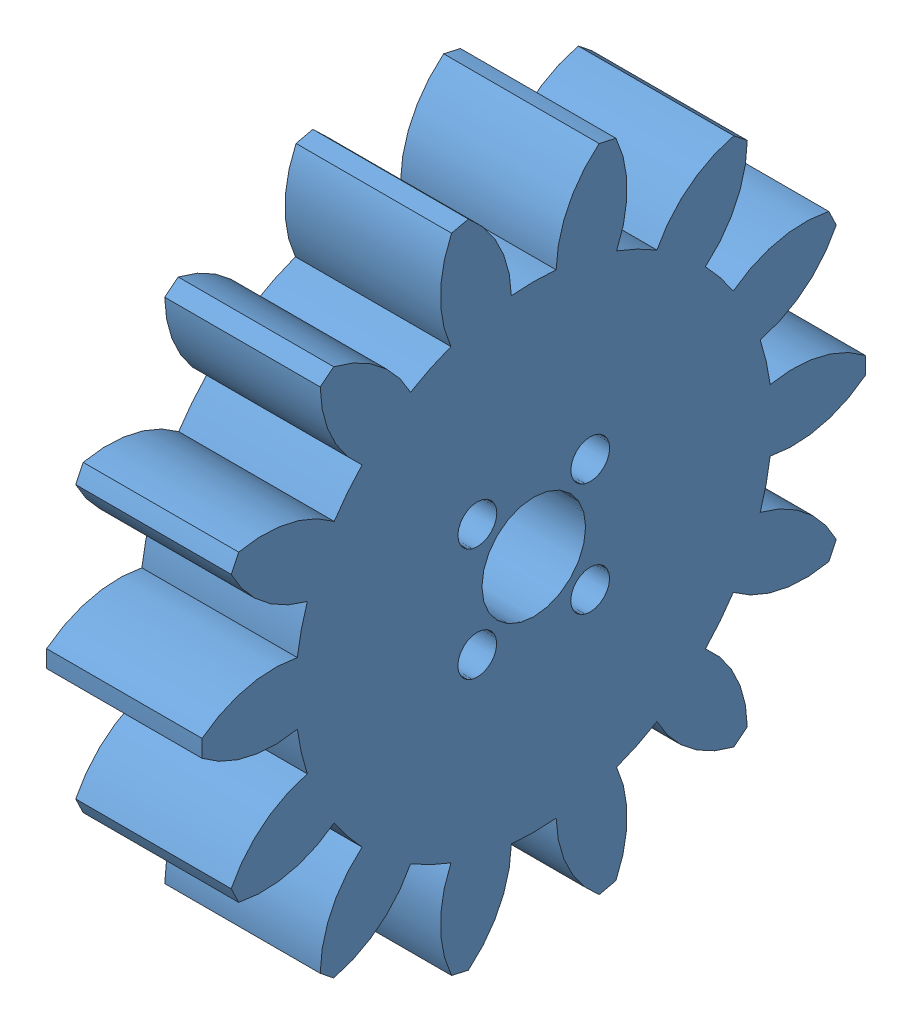
SolidWorks assembly ARMUS-REV4-500, configuration Défaut. Lengths in mm.
Overall size (28.58 79.69 81.28).
2 component instances, 2 part files, 4 mates.
Components (placement in the parent):
- ARMUS-REV4-501-1: ARMUS-REV4-501 [Défaut] at origin size (19.05 79.69 81.28)
- bore_set_screw_D_hub-1: bore_set_screw_D_hub [Défaut] at (-20.7023 -52.5937 -16.7801) x (0 -1 0.000796) z (0 0.000796 1) size (20.57 9.61 20.57)
Mates (geometry in assembly coordinates):
- Coincident1: coordinate: point of ARMUS-REV2-X01-1
- Concentric1: concentric anti-aligned: cylinder of ARMUS-REV2-X01-1 through (0 -6.91 6.921) axis (1 0 0) radius 2.3813; cylinder of bore_set_screw_D_hub-1 through (0 -6.91 6.921) axis (-1 0 0) radius 3.3722
- Concentric3: concentric anti-aligned: cylinder of ARMUS-REV2-X01-1 through (50.8001 0 0) axis (-1 0 0) radius 6.35; cylinder of bore_set_screw_D_hub-1 through (0 -0.0007 0.0007) axis (1 0 0) radius 3.175
- Coincident2: coincident anti-aligned: plane of ARMUS-REV2-X01-1 through (0 0 0) normal (-1 0 0); plane of bore_set_screw_D_hub-1 through (0 3.4539 -3.4594) normal (1 0 0)
